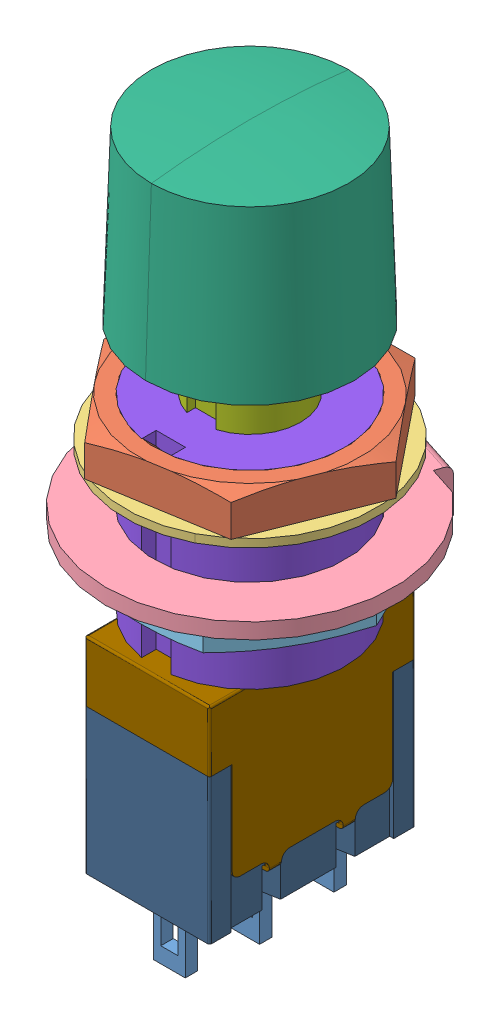
SolidWorks assembly MB2065SB1W01_DA, configuration Default. Lengths in mm.
Overall size (23.9 44.48 23.66).
10 component instances, 10 part files, 9 mates.
Components (placement in the parent):
- MB2065SB1W01_DA_3-1: MB2065SB1W01_DA_3 [Default] at (0 -8.9154 0) size (2.82 5 12.5)
- MB2065SB1W01_DA_5-1: MB2065SB1W01_DA_5 [Default] at (0 14.6304 0) x (-0.627906 0 -0.77829) z (0 1 0) size (16.01 17.78 2.4)
- MB2065SB1W01_DA_7-1: MB2065SB1W01_DA_7 [Default] at (0 13.1826 0) x (-0.451917 0 -0.89206) z (0 1 0) size (15.8 15.8 0.51)
- MB2065SB1W01_DA_9-1: MB2065SB1W01_DA_9 [Default] at (0 9.7286 0) x (-0.3072 0 0.951645) z (0 -1 0) size (18.62 18.21 2.79)
- MB2065SB1W01_DA_11-1: MB2065SB1W01_DA_11 [Default] at (0 7.7347 0) x (-1 0 0) z (0 1 0) size (16.01 17.78 2.02)
- MB2065SB1W01_DA_13-1: MB2065SB1W01_DA_13 [Default] at (0 19.812 0) x (-1 0 0) z (0 0 -1) size (13.21 11 13.21)
- MB2065SB1W01_DA_15-1: MB2065SB1W01_DA_15 [Default] at (0 15.8242 0) x (-1 0 0) z (0 0 -1) size (6.4 5.28 6.13)
- MB2065SB1W01_DA_17-1: MB2065SB1W01_DA_17 [Default] at (0 3.8354 0) x (-1 0 0) z (0 0 -1) size (11.99 11.99 11.92)
- MB2065SB1W01_DA_19-1: MB2065SB1W01_DA_19 [Default] at (0 3.5814 0) size (7.9 10.96 13)
- MB2065SB1W01_DA_21-1: MB2065SB1W01_DA_21 [Default] at origin size (7.9 13.26 13)
Mates (geometry in assembly coordinates):
- Concentric1: concentric aligned: circle of MB2065SB1W01_DA_5-1; cylinder of MB2065SB1W01_DA_17-1 through (0 15.8242 0) axis (0 -1 0) radius 5.9944
- Concentric2: concentric aligned: circle of MB2065SB1W01_DA_9-1; cylinder of MB2065SB1W01_DA_17-1 through (0 15.8242 0) axis (0 -1 0) radius 5.9944
- Concentric3: concentric aligned: circle of MB2065SB1W01_DA_11-1; cylinder of MB2065SB1W01_DA_17-1 through (0 15.8242 0) axis (0 -1 0) radius 5.9944
- Concentric4: concentric aligned: cylinder of MB2065SB1W01_DA_7-1 through (0 13.4366 0) axis (0 -1 0) radius 7.8994; cylinder of MB2065SB1W01_DA_17-1 through (0 15.8242 0) axis (0 -1 0) radius 5.9944
- Concentric5: concentric aligned: circle of MB2065SB1W01_DA_11-1; cylinder of MB2065SB1W01_DA_17-1 through (0 15.8242 0) axis (0 -1 0) radius 5.9944
- Coincident11: coincident aligned: plane of MB2065SB1W01_DA_5-1 through (0 15.8242 0) normal (0 1 0); plane of MB2065SB1W01_DA_17-1 through (0 15.8242 0) normal (0 1 0)
- Coincident12: coincident anti-aligned: plane of MB2065SB1W01_DA_5-1 through (-6.5355 13.4366 5.2727) normal (0 -1 0); plane of MB2065SB1W01_DA_7-1 through (0 13.4366 0) normal (0 1 0)
- Coincident13: coincident anti-aligned: plane of MB2065SB1W01_DA_9-1 through (0 8.738 0) normal (0 -1 0); plane of MB2065SB1W01_DA_11-1 through (0 8.738 0) normal (0 1 0)
- Distance1: distance = 3.2 mm anti-aligned: plane of MB2065SB1W01_DA_9-1 through (0 9.7286 0) normal (0 1 0); plane of MB2065SB1W01_DA_7-1 through (0 12.9286 0) normal (0 -1 0)
